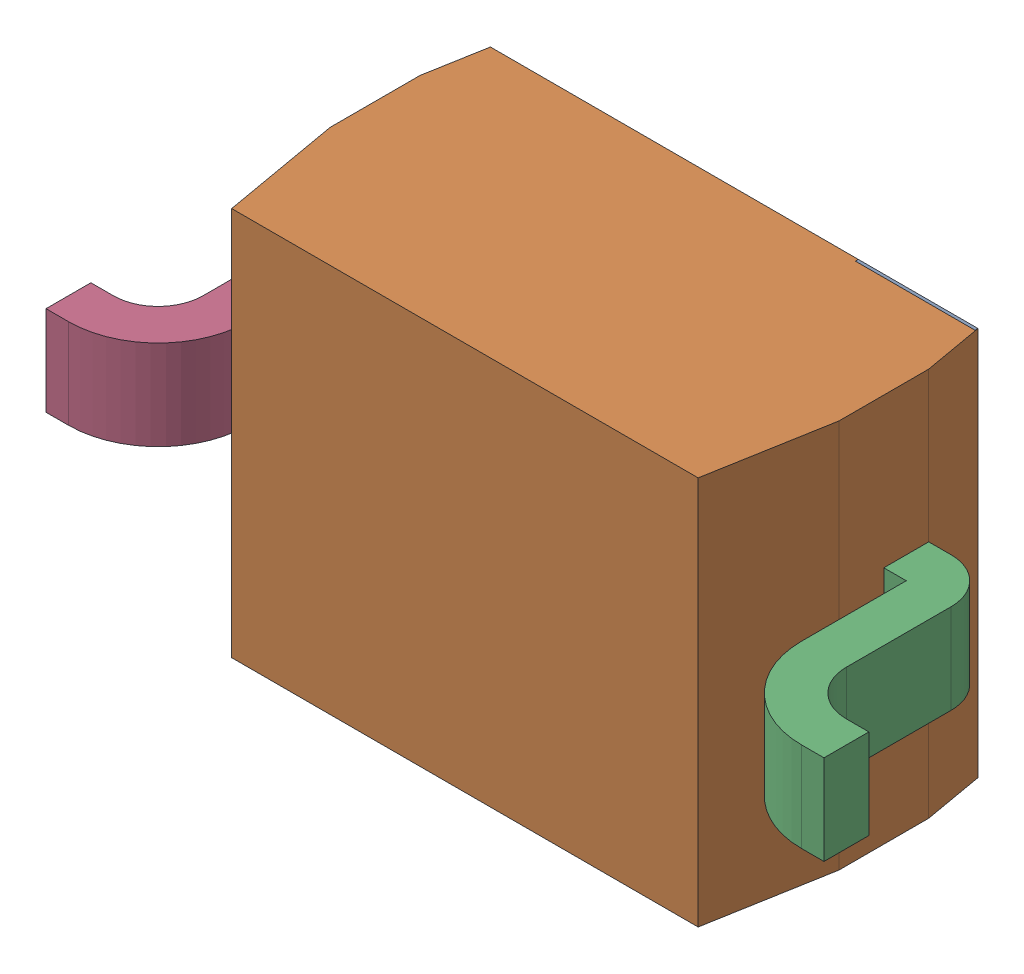
SolidWorks assembly D2, configuration 默认. Lengths in mm.
Overall size (2.6 1.3 1).
5 component instances, 4 part files, 0 mates.
Components (placement in the parent):
- D2-subassembly-1-1: D2-subassembly-1 [默认] at (13.4621 13.5889 -1.6914) x (1 0 0) z (0 0 -1) size (2.6 1.3 1)
  - SOD-323-1: SOD-323 [默认] at origin size (0.4 1.3 0.01)
  - SOD-323-1-1: SOD-323-1 [默认] at origin size (1.7 1.3 0.9)
  - SOD-323-2-1: SOD-323-2 [默认] at origin size (0.45 0.3 0.8)
  - SOD-323-3-1: SOD-323-3 [默认] at origin size (0.45 0.3 0.8)
